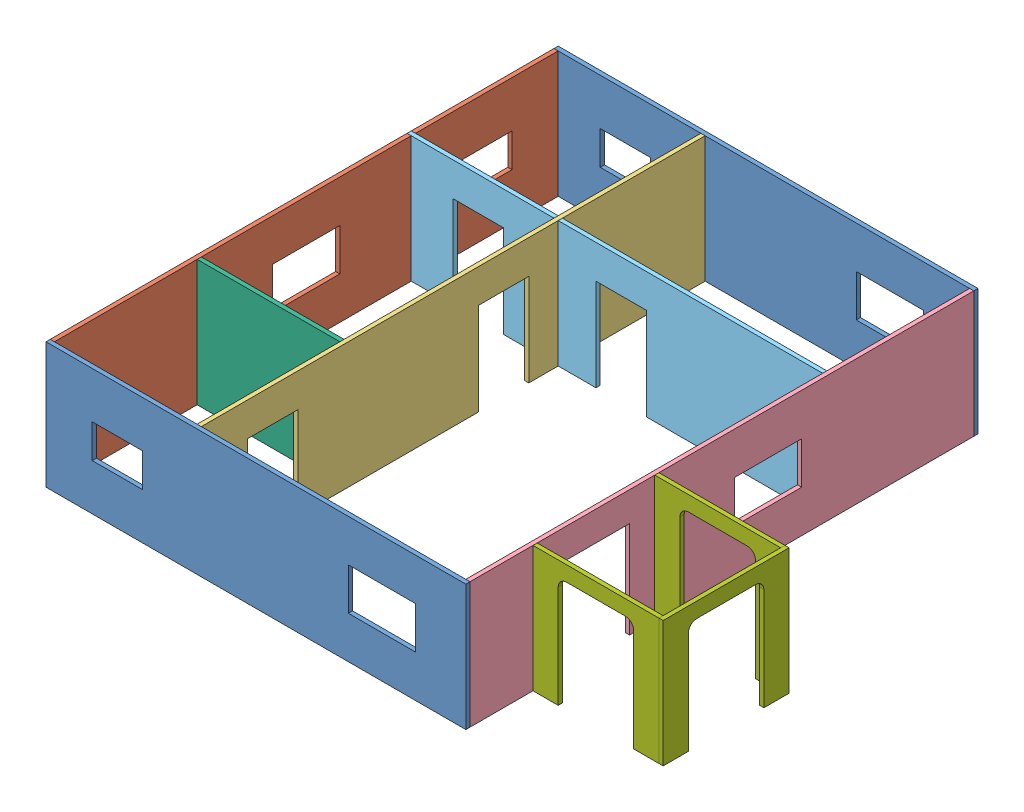
SolidWorks assembly Assem1, configuration Default. Lengths in mm.
Overall size (655 150 610).
10 component instances, 7 part files, 28 mates.
Components (placement in the parent):
- Part1-1: Part1 [Default] at (200.9003 276.4983 363.1873) size (500 150 5)
- Part5-1: Part5 [Default] at (-44.0997 276.4983 63.1873) x (0 0 1) z (-1 0 0) size (600 150 5)
- Part1-2: Part1 [Default] at (200.9003 276.4983 -241.8127) size (500 150 5)
- Part2-1: Part2 [Default] at (130.9003 276.4983 63.1873) x (0 0 1) z (-1 0 0) size (600 150 5)
- Part3-2: Part3 [Default] at (450.9003 276.4983 63.1873) x (0 0 1) z (-1 0 0) size (600 150 5)
- Part4-1: Part4 [Default] at (198.4003 276.4983 -61.8127) x (-1 0 0) z (0 0 -1) size (495 150 5)
- Part6-1: Part6 [Default] at (40.9003 276.4983 188.1873) size (170 150 5)
- Part7-1: Part7 [Default] at (525.9003 276.4983 283.1873) size (150 150 5)
- Part7-2: Part7 [Default] at (525.9003 276.4983 138.1873) size (150 150 5)
- Part7-3: Part7 [Default] at (605.9003 276.4983 213.1873) x (0 0 1) z (-1 0 0) size (150 150 5)
Mates (geometry in assembly coordinates):
- Parallel1: parallel anti-aligned: plane of Part1-1 through (200.9003 276.4983 363.1873) normal (0 0 -1); plane of Part5-1 through (-49.0997 351.4983 363.1873) normal (0 0 1)
- Coincident3: coincident aligned: plane of Part1-1 through (-49.0997 351.4983 368.1873) normal (0 1 0); plane of Part5-1 through (-49.0997 351.4983 -236.8127) normal (0 1 0)
- Coincident8: coincident aligned: plane of Part5-1 through (-49.0997 276.4983 63.1873) normal (-1 0 0); plane of Part1-2 through (-49.0997 351.4983 -236.8127) normal (-1 0 0)
- Coincident9: coincident anti-aligned: plane of Part5-1 through (-49.0997 351.4983 -236.8127) normal (0 0 -1); plane of Part1-2 through (200.9003 276.4983 -236.8127) normal (0 0 1)
- Coincident10: coincident aligned: plane of Part5-1 through (-49.0997 351.4983 -236.8127) normal (0 1 0); plane of Part1-2 through (-49.0997 351.4983 -236.8127) normal (0 1 0)
- Coincident12: coincident aligned: plane of Part1-2 through (-49.0997 351.4983 -236.8127) normal (0 1 0); plane of Part2-1 through (125.9003 351.4983 -236.8127) normal (0 1 0)
- Coincident15: coincident aligned: plane of Part1-2 through (-49.0997 351.4983 -236.8127) normal (0 1 0); plane of Part3-2 through (445.9003 351.4983 -236.8127) normal (0 1 0)
- Coincident17: coincident anti-aligned: plane of Part1-2 through (200.9003 276.4983 -236.8127) normal (0 0 1); plane of Part2-1 through (125.9003 351.4983 -236.8127) normal (0 0 -1)
- Distance1: distance = 170 mm anti-aligned: plane of Part2-1 through (125.9003 276.4983 63.1873) normal (-1 0 0); plane of Part5-1 through (-44.0997 276.4983 63.1873) normal (1 0 0)
- Coincident19: coincident anti-aligned: plane of Part1-1 through (200.9003 276.4983 363.1873) normal (0 0 -1); plane of Part2-1 through (125.9003 351.4983 363.1873) normal (0 0 1)
- Coincident20: coincident aligned: plane of Part1-1 through (-49.0997 351.4983 368.1873) normal (-1 0 0); plane of Part5-1 through (-49.0997 276.4983 63.1873) normal (-1 0 0)
- Coincident21: coincident anti-aligned: plane of Part1-1 through (200.9003 276.4983 363.1873) normal (0 0 -1); plane of Part3-2 through (445.9003 351.4983 363.1873) normal (0 0 1)
- Coincident23: coincident aligned: plane of Part1-2 through (450.9003 351.4983 -236.8127) normal (1 0 0); plane of Part3-2 through (450.9003 276.4983 63.1873) normal (1 0 0)
- Coincident24: coincident: plane of Part1-1 through (-49.0997 351.4983 368.1873) normal (0 1 0); plane of Part4-1 through (445.9003 277.9498 -159.421) normal (0 1 0)
- Distance2: distance = 170 mm: plane of Part4-1 through (198.4003 276.4983 -66.8127) normal (0 0 -1); plane of Part1-2 through (200.9003 276.4983 -236.8127) normal (0 0 1)
- Coincident29: coincident aligned: plane of Part5-1 through (-49.0997 351.4983 -236.8127) normal (0 1 0); plane of Part6-1 through (-44.0997 351.4983 193.1873) normal (0 1 0)
- Coincident30: coincident anti-aligned: plane of Part2-1 through (125.9003 276.4983 63.1873) normal (-1 0 0); plane of Part6-1 through (125.9003 351.4983 193.1873) normal (1 0 0)
- Distance3: distance = 170 mm anti-aligned: plane of Part6-1 through (40.9003 276.4983 193.1873) normal (0 0 1); plane of Part1-1 through (200.9003 276.4983 363.1873) normal (0 0 -1)
- Coincident32: coincident aligned: plane of Part3-2 through (445.9003 351.4983 -236.8127) normal (0 1 0); plane of Part7-1 through (450.9003 351.4983 288.1873) normal (0 1 0)
- Coincident33: coincident anti-aligned: plane of Part3-2 through (450.9003 276.4983 63.1873) normal (1 0 0); plane of Part7-1 through (450.9003 351.4983 288.1873) normal (-1 0 0)
- Distance4: distance = 30 mm aligned: plane of Part3-2 through (445.9003 201.4983 253.1873) normal (0 0 -1); plane of Part7-1 through (490.9003 323.4983 283.1873) normal (0 0 -1)
- Coincident35: coincident aligned: plane of Part3-2 through (445.9003 351.4983 -236.8127) normal (0 1 0); plane of Part7-2 through (450.9003 351.4983 143.1873) normal (0 1 0)
- Coincident36: coincident anti-aligned: plane of Part3-2 through (450.9003 276.4983 63.1873) normal (1 0 0); plane of Part7-2 through (450.9003 351.4983 143.1873) normal (-1 0 0)
- Distance5: distance = 30 mm aligned: plane of Part7-2 through (490.9003 323.4983 143.1873) normal (0 0 1); plane of Part3-2 through (445.9003 316.4983 173.1873) normal (0 0 1)
- Coincident38: coincident anti-aligned: plane of Part7-1 through (600.9003 351.4983 288.1873) normal (1 0 0); plane of Part7-3 through (600.9003 323.4983 178.1873) normal (-1 0 0)
- Coincident39: coincident aligned: plane of Part7-1 through (450.9003 351.4983 288.1873) normal (0 1 0); plane of Part7-3 through (600.9003 351.4983 138.1873) normal (0 1 0)
- Coincident40: coincident aligned: plane of Part7-1 through (490.9003 323.4983 288.1873) normal (0 0 1); plane of Part7-3 through (600.9003 351.4983 288.1873) normal (0 0 1)
- Coincident41: coincident anti-aligned: plane of Part3-2 through (445.9003 276.4983 63.1873) normal (-1 0 0); plane of Part4-1 through (445.9003 351.4983 -66.8127) normal (1 0 0)
